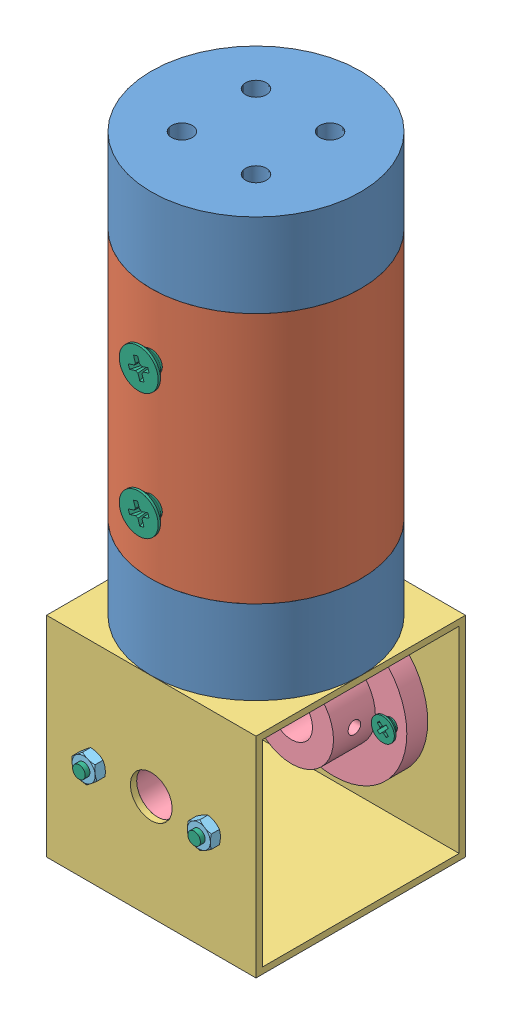
SolidWorks assembly Elo3-Assembly, configuration Valor predeterminado. Lengths in mm.
Overall size (50 150 57.04).
23 component instances, 6 part files, 18 mates.
Components (placement in the parent):
- Conector Nylon-1: Conector Nylon [Valor predeterminado] at (-9.7647 -0.8397 50) size (50 50 50)
- Conector PVC 3-4-1: Conector PVC 3-4 [Valor predeterminado] at (-9.7647 -0.8397 50) size (50 60 50)
- Conector Nylon-2: Conector Nylon [Valor predeterminado] at (-9.7647 59.1603 50) x (1 0 0) z (0 0 -1) size (50 50 50)
- Caixa Alumínio-1: Caixa Alumínio [Valor predeterminado] at (40.2353 -47.1118 60.4524) x (0 0 1) z (-1 0 0) size (57.04 50 50)
  - Caixa Aluminio 1-1: Caixa Aluminio 1 [Valor predeterminado] at (-10.4524 1.2722 25) size (50 50 50)
  - Bucha 10 mm-1: Bucha 10 mm [Valor predeterminado] at (-33.9524 1.2722 50) x (0 -1 0) z (0 0 1) size (35 15 35)
  - Bucha 10 mm-2: Bucha 10 mm [Valor predeterminado] at (13.0476 1.2722 50) x (0 1 0) z (0 0 1) size (35 15 35)
  - hex nut style 1 gradeab_iso-1: hex nut style 1 gradeab_iso [ISO - 4032 - M3 - D - N] at (14.5476 1.2722 36.25) x (0 -0.866025 0.5) z (-1 0 0) size (5.5 6.35 2.4)
  - countersunk flat head cross recess screw_iso-1: countersunk flat head cross recess screw_iso [ISO 7046-1 - M3 x 12 - Z - 12N] at (6.0663 1.2722 36.25) x (1 0 0) z (0 -0.400835 0.91615) size (12 5.5 5.5)
  - hex nut style 1 gradeab_iso-2: hex nut style 1 gradeab_iso [ISO - 4032 - M3 - D - N] at (-35.4524 1.2722 36.25) x (0 0.249017 -0.968499) z (1 0 0) size (5.5 6.35 2.4)
  - countersunk flat head cross recess screw_iso-2: countersunk flat head cross recess screw_iso [ISO 7046-1 - M3 x 12 - Z - 12N] at (-26.971 1.2722 36.25) x (-1 0 0) z (0 -0.725577 0.688141) size (12 5.5 5.5)
  - hex nut style 1 gradeab_iso-3: hex nut style 1 gradeab_iso [ISO - 4032 - M3 - D - N] at (14.5476 1.2722 63.75) x (0 -0.934192 0.356771) z (-1 0 0) size (5.5 6.35 2.4)
  - countersunk flat head cross recess screw_iso-3: countersunk flat head cross recess screw_iso [ISO 7046-1 - M3 x 12 - Z - 12N] at (6.0663 1.2722 63.75) x (1 0 0) z (0 -0.540657 0.841243) size (12 5.5 5.5)
  - countersunk flat head cross recess screw_iso-4: countersunk flat head cross recess screw_iso [ISO 7046-1 - M3 x 12 - Z - 12N] at (-26.971 1.2722 63.75) x (-1 0 0) z (0 -0.594897 0.803802) size (12 5.5 5.5)
  - hex nut style 1 gradeab_iso-4: hex nut style 1 gradeab_iso [ISO - 4032 - M3 - D - N] at (-35.4524 1.2722 63.75) x (0 0.146862 -0.989157) z (1 0 0) size (5.5 6.35 2.4)
- countersunk flat head cross recess screw_iso-1: countersunk flat head cross recess screw_iso [ISO 7046-1 - M5 x 16 - Z - 16N] at (-18.6035 -25.5782 41.1612) x (0 1 0) z (-0.840032 0 -0.542537) size (16 9.3 9.3)
- countersunk flat head cross recess screw_iso-2: countersunk flat head cross recess screw_iso [ISO 7046-1 - M5 x 16 - Z - 16N] at (-18.6035 -25.5782 58.8388) x (0 1 0) z (-0.840032 0 -0.542537) size (16 9.3 9.3)
- countersunk flat head cross recess screw_iso-3: countersunk flat head cross recess screw_iso [ISO 7046-1 - M5 x 16 - Z - 16N] at (-0.9259 -25.5782 41.1612) x (0 1 0) z (-0.840032 0 -0.542537) size (16 9.3 9.3)
- countersunk flat head cross recess screw_iso-4: countersunk flat head cross recess screw_iso [ISO 7046-1 - M5 x 16 - Z - 16N] at (-0.9259 -25.5782 58.8388) x (0 1 0) z (-0.840032 0 -0.542537) size (16 9.3 9.3)
- countersunk flat head cross recess screw_iso-5: countersunk flat head cross recess screw_iso [ISO 7046-1 - M5 x 10 - Z - 10N] at (-9.7647 14.1603 78) x (0 0 -1) z (-0.312384 0.949956 0) size (10 9.3 9.3)
- countersunk flat head cross recess screw_iso-6: countersunk flat head cross recess screw_iso [ISO 7046-1 - M5 x 10 - Z - 10N] at (-9.7647 14.1603 22) x (0 0 1) z (-0.075322 0.997159 0) size (10 9.3 9.3)
- countersunk flat head cross recess screw_iso-7: countersunk flat head cross recess screw_iso [ISO 7046-1 - M5 x 10 - Z - 10N] at (-9.7647 44.1603 22) x (0 0 1) z (-0.075322 0.997159 0) size (10 9.3 9.3)
- countersunk flat head cross recess screw_iso-8: countersunk flat head cross recess screw_iso [ISO 7046-1 - M5 x 10 - Z - 10N] at (-9.7647 44.1603 78) x (0 0 -1) z (-0.312384 0.949956 0) size (10 9.3 9.3)
Mates (geometry in assembly coordinates):
- Concentric1: concentric: cylinder of Conector Nylon-1 through (-9.7647 14.1603 75.8) axis (0 0 1) radius 2.1; cylinder of Conector PVC 3-4-1 through (-9.7647 14.1603 25) axis (0 0 1) radius 2.5
- Coincident1: coincident: cylinder of Conector Nylon-1 through (-9.7647 29.1603 50) axis (0 -1 0) radius 22; circle of Conector PVC 3-4-1
- Concentric2: concentric: cylinder of Conector PVC 3-4-1 through (-9.7647 44.1603 25) axis (0 0 1) radius 2.5; cylinder of Conector Nylon-2 through (-9.7647 44.1603 24.2) axis (0 0 -1) radius 2.1
- Concentric3: concentric: cylinder of Conector PVC 3-4-1 through (-9.7647 59.1603 50) axis (0 -1 0) radius 22; cylinder of Conector Nylon-2 through (-9.7647 29.1603 50) axis (0 1 0) radius 22
- Coincident2: coincident: circle of Conector Nylon-1; circle of Caixa Alumínio-1/Caixa Aluminio 1-1
- Coincident3: coincident: cylinder of Conector Nylon-1 through (-0.9259 -5.8397 41.1612) axis (0 -1 0) radius 2.5; circle of Caixa Alumínio-1/Caixa Aluminio 1-1
- Coincident4: coincident: circle of Caixa Alumínio-1/Caixa Aluminio 1-1; circle of countersunk flat head cross recess screw_iso-1
- Coincident5: coincident: circle of Caixa Alumínio-1/Caixa Aluminio 1-1; circle of countersunk flat head cross recess screw_iso-2
- Coincident6: coincident: circle of Caixa Alumínio-1/Caixa Aluminio 1-1; circle of countersunk flat head cross recess screw_iso-3
- Coincident7: coincident: circle of Caixa Alumínio-1/Caixa Aluminio 1-1; circle of countersunk flat head cross recess screw_iso-4
- Coincident8: coincident: cylinder of Conector PVC 3-4-1 through (-9.7647 14.1603 25) axis (0 0 1) radius 2.5; circle of countersunk flat head cross recess screw_iso-5
- Distance1: distance = 3 mm: plane of countersunk flat head cross recess screw_iso-5 through (-9.7647 14.1603 78) normal (0 0 1); plane of Caixa Alumínio-1/Caixa Aluminio 1-1 through (-34.7647 -70.8397 75) normal (0 0 1)
- Coincident10: coincident: cylinder of ? through (-9.7647 14.1603 25) axis (0 0 1) radius 2.5; circle of countersunk flat head cross recess screw_iso-6
- Distance2: distance = 3 mm: plane of countersunk flat head cross recess screw_iso-6 through (-9.7647 14.1603 22) normal (0 0 -1); plane of Caixa Alumínio-1/Caixa Aluminio 1-1 through (-34.7647 -70.8397 25) normal (0 0 -1)
- Coincident12: coincident: cylinder of Conector PVC 3-4-1 through (-9.7647 44.1603 25) axis (0 0 1) radius 2.5; circle of countersunk flat head cross recess screw_iso-7
- Coincident13: coincident: plane of countersunk flat head cross recess screw_iso-6 through (-9.7647 14.1603 22) normal (0 0 -1); plane of countersunk flat head cross recess screw_iso-7 through (-9.7647 44.1603 22) normal (0 0 -1)
- Coincident14: coincident: cylinder of Conector PVC 3-4-1 through (-9.7647 44.1603 25) axis (0 0 1) radius 2.5; circle of countersunk flat head cross recess screw_iso-8
- Coincident15: coincident: plane of countersunk flat head cross recess screw_iso-5 through (-9.7647 14.1603 78) normal (0 0 1); plane of countersunk flat head cross recess screw_iso-8 through (-9.7647 44.1603 78) normal (0 0 1)
